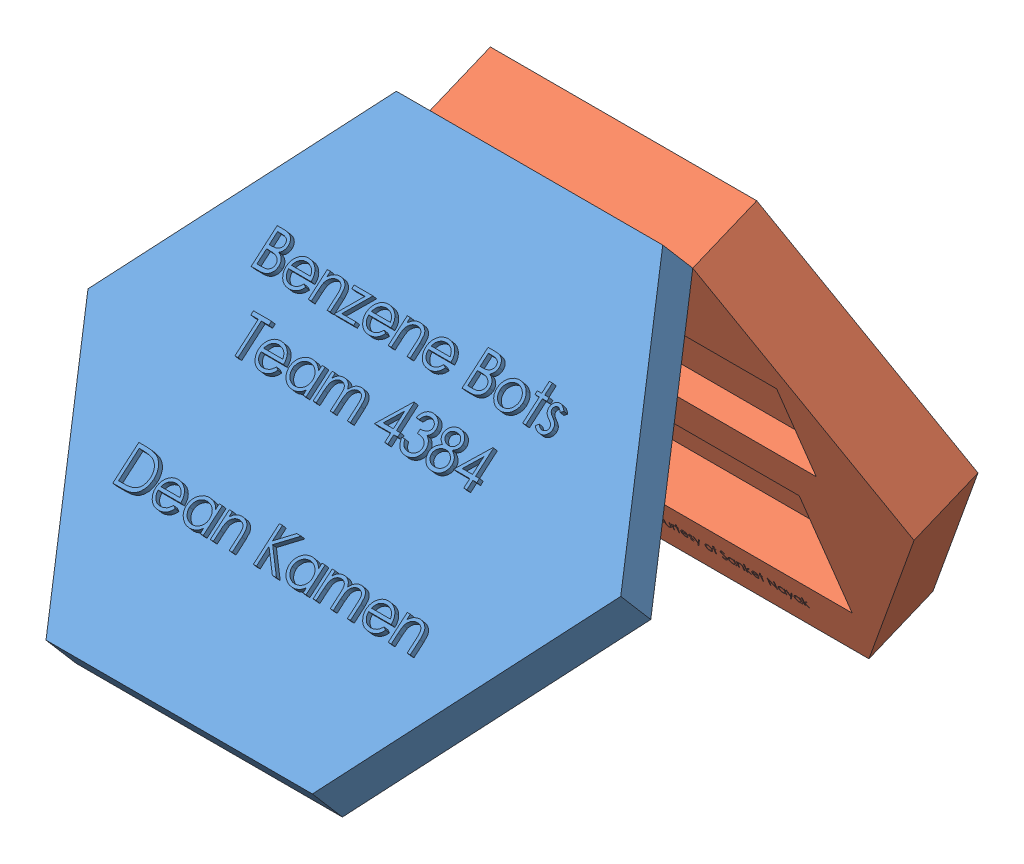
SolidWorks assembly Dean Kamen Nametag Enclosure, configuration Default. Lengths in mm.
Overall size (146.65 128.23 171.84).
2 component instances, 2 part files, 2 mates.
Components (placement in the parent):
- Dean Kamen Nametag Enclosure Top-1: Dean Kamen Nametag Enclosure Top [Default] at (10.5069 64.2724 100.8818) x (1 0 0) z (0 -0.650655 0.759373) size (146.65 14.29 127)
- Dean Kamen Nametag Enclosure Bottom-1: Dean Kamen Nametag Enclosure Bottom [Default] at (10.5069 46.9007 28.4142) x (-1 0 0) z (0 -0.924225 -0.381849) size (146.65 19.05 127)
Mates (geometry in assembly coordinates):
- Coincident1: coincident anti-aligned: line of Dean Kamen Nametag Enclosure Top-1 through (47.1686 105.589 52.6616) axis (-1 0 0); line of Dean Kamen Nametag Enclosure Bottom-1 through (-26.1548 105.589 52.6616) axis (1 0 0)
- Coincident2: coincident: point of Dean Kamen Nametag Enclosure Top-1; point of Dean Kamen Nametag Enclosure Bottom-1
